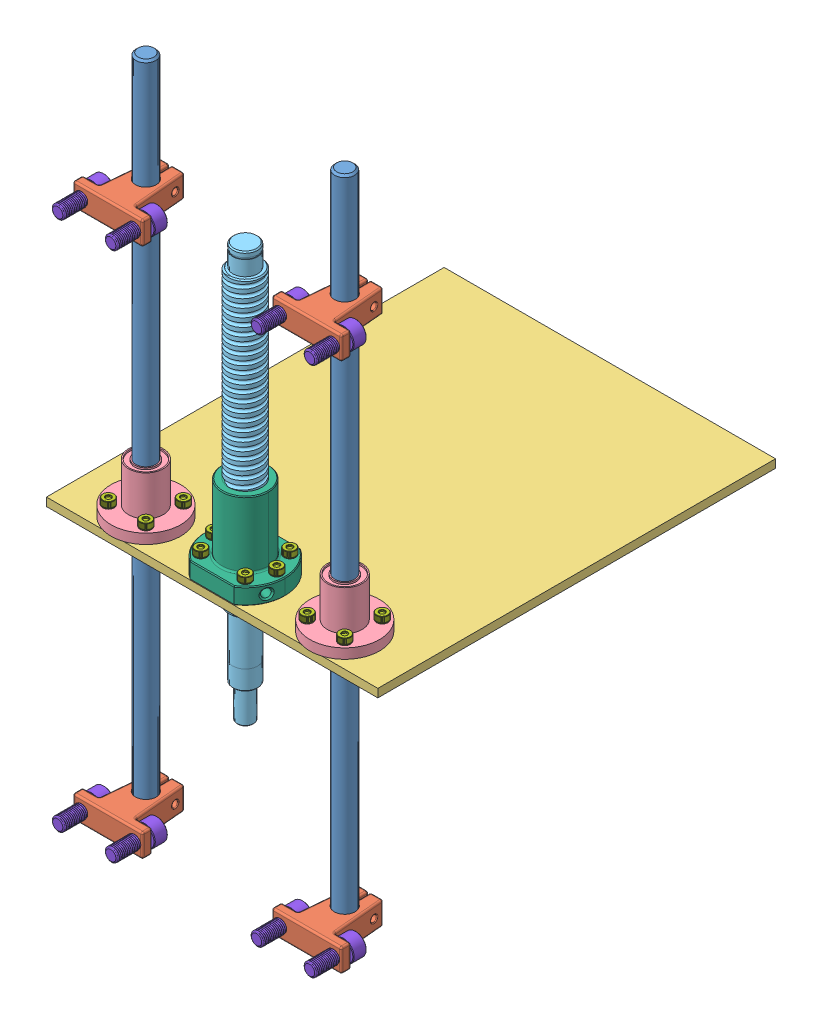
SolidWorks assembly Z_Axis_motion, configuration Default. Lengths in mm.
Overall size (200 400 257.52).
33 component instances, 8 part files, 23 mates.
Components (placement in the parent):
- 6112K104_Linear Motion Shaft-1: 6112K104_Linear Motion Shaft [6112K104] at (60 193 127) x (0.99915 0 0.041223) z (0 -1 0) size (12 12 400)
- 61815K34_Base-Mounted Shaft Support-1: 61815K34_Base-Mounted Shaft Support [61815K34] at (60 0 150) x (1 0 0) z (0 1 0) size (42 38 14)
- BuildPlate-1: BuildPlate [Default] at (0 145.6732 27) x (-1 0 0) z (0 0 -1) size (200 5 240)
- Linear Bearing-1: Linear Bearing [Default] at (-60 150.6732 127) x (-0.707107 0 0.707107) z (-0.707107 0 -0.707107) size (42 30 42)
- 61815K34_Base-Mounted Shaft Support-2: 61815K34_Base-Mounted Shaft Support [61815K34] at (60 320 150) x (1 0 0) z (0 1 0) size (42 38 14)
- 61815K34_Base-Mounted Shaft Support-3: 61815K34_Base-Mounted Shaft Support [61815K34] at (-60 0 150) x (1 0 0) z (0 1 0) size (42 38 14)
- 61815K34_Base-Mounted Shaft Support-4: 61815K34_Base-Mounted Shaft Support [61815K34] at (-60 320 150) x (1 0 0) z (0 1 0) size (42 38 14)
- Linear Bearing-2: Linear Bearing [Default] at (60 150.6732 127) x (-0.707107 0 -0.707107) z (0.707107 0 -0.707107) size (42 30 42)
- Generic Ballscrew-1: Generic Ballscrew [SFU-2005] at (0 74.038 127) x (-0.837169 0 -0.546944) z (0 -1 0) size (20 20.92 250)
- 6112K104_Linear Motion Shaft-2: 6112K104_Linear Motion Shaft [6112K104] at (-60 193 127) x (1 0 0) z (0 -1 0) size (12 12 400)
- SFU-1605.step-1: SFU-1605.step [Default] at (0 150.6732 127) x (1 0 0) z (0 -1 0) size (48 40 52.06)
- 91290A144_Black-Oxide Alloy Steel Socket Head Screw-1: 91290A144_Black-Oxide Alloy Steel Socket Head Screw [91290A144] at (71.3137 153.6732 138.3137) x (1 0 0) z (0 1 0) size (7 7 14.17)
- 91290A144_Black-Oxide Alloy Steel Socket Head Screw-2: 91290A144_Black-Oxide Alloy Steel Socket Head Screw [91290A144] at (48.6863 153.6732 138.3137) x (0 0 1) z (0 1 0) size (7 7 14.17)
- 91290A144_Black-Oxide Alloy Steel Socket Head Screw-3: 91290A144_Black-Oxide Alloy Steel Socket Head Screw [91290A144] at (48.6863 153.6732 115.6863) x (-1 0 0) z (0 1 0) size (7 7 14.17)
- 91290A144_Black-Oxide Alloy Steel Socket Head Screw-4: 91290A144_Black-Oxide Alloy Steel Socket Head Screw [91290A144] at (71.3137 153.6732 115.6863) x (0 0 -1) z (0 1 0) size (7 7 14.17)
- 91290A144_Black-Oxide Alloy Steel Socket Head Screw-5: 91290A144_Black-Oxide Alloy Steel Socket Head Screw [91290A144] at (-71.3137 153.6732 138.3137) x (1 0 0) z (0 1 0) size (7 7 14.17)
- 91290A144_Black-Oxide Alloy Steel Socket Head Screw-6: 91290A144_Black-Oxide Alloy Steel Socket Head Screw [91290A144] at (-48.6863 153.6732 138.3137) x (0 0 -1) z (0 1 0) size (7 7 14.17)
- 91290A144_Black-Oxide Alloy Steel Socket Head Screw-7: 91290A144_Black-Oxide Alloy Steel Socket Head Screw [91290A144] at (-48.6863 153.6732 115.6863) x (-1 0 0) z (0 1 0) size (7 7 14.17)
- 91290A144_Black-Oxide Alloy Steel Socket Head Screw-8: 91290A144_Black-Oxide Alloy Steel Socket Head Screw [91290A144] at (-71.3137 153.6732 115.6863) x (0 0 1) z (0 1 0) size (7 7 14.17)
- 96144A211_Fine-Thread Alloy Steel Socket Head Screw-1: 96144A211_Fine-Thread Alloy Steel Socket Head Screw [96144A211] at (76 0 164.1985) size (13 13 28.66)
- 96144A211_Fine-Thread Alloy Steel Socket Head Screw-2: 96144A211_Fine-Thread Alloy Steel Socket Head Screw [96144A211] at (44 0 164.1985) size (13 13 28.66)
- 96144A211_Fine-Thread Alloy Steel Socket Head Screw-3: 96144A211_Fine-Thread Alloy Steel Socket Head Screw [96144A211] at (44 320 164.1985) size (13 13 28.66)
- 96144A211_Fine-Thread Alloy Steel Socket Head Screw-4: 96144A211_Fine-Thread Alloy Steel Socket Head Screw [96144A211] at (-76 0 164.1985) size (13 13 28.66)
- 96144A211_Fine-Thread Alloy Steel Socket Head Screw-5: 96144A211_Fine-Thread Alloy Steel Socket Head Screw [96144A211] at (-76 320 164.1985) size (13 13 28.66)
- 96144A211_Fine-Thread Alloy Steel Socket Head Screw-6: 96144A211_Fine-Thread Alloy Steel Socket Head Screw [96144A211] at (76 320 164.1985) size (13 13 28.66)
- 96144A211_Fine-Thread Alloy Steel Socket Head Screw-7: 96144A211_Fine-Thread Alloy Steel Socket Head Screw [96144A211] at (-44 0 164.1985) size (13 13 28.66)
- 96144A211_Fine-Thread Alloy Steel Socket Head Screw-8: 96144A211_Fine-Thread Alloy Steel Socket Head Screw [96144A211] at (-44 320 164.1985) size (13 13 28.66)
- 91290A144_Black-Oxide Alloy Steel Socket Head Screw-9: 91290A144_Black-Oxide Alloy Steel Socket Head Screw [91290A144] at (-13.435 157.6732 113.565) x (1 0 0) z (0 1 0) size (7 7 14.17)
- 91290A144_Black-Oxide Alloy Steel Socket Head Screw-10: 91290A144_Black-Oxide Alloy Steel Socket Head Screw [91290A144] at (-19 157.6732 127) x (0.707107 0 -0.707107) z (0 1 0) size (7 7 14.17)
- 91290A144_Black-Oxide Alloy Steel Socket Head Screw-11: 91290A144_Black-Oxide Alloy Steel Socket Head Screw [91290A144] at (-13.435 157.6732 140.435) x (0 0 -1) z (0 1 0) size (7 7 14.17)
- 91290A144_Black-Oxide Alloy Steel Socket Head Screw-12: 91290A144_Black-Oxide Alloy Steel Socket Head Screw [91290A144] at (13.435 157.6732 113.565) x (1 0 0) z (0 1 0) size (7 7 14.17)
- 91290A144_Black-Oxide Alloy Steel Socket Head Screw-13: 91290A144_Black-Oxide Alloy Steel Socket Head Screw [91290A144] at (19 157.6732 127) x (0.707107 0 0.707107) z (0 1 0) size (7 7 14.17)
- 91290A144_Black-Oxide Alloy Steel Socket Head Screw-14: 91290A144_Black-Oxide Alloy Steel Socket Head Screw [91290A144] at (13.435 157.6732 140.435) x (0 0 1) z (0 1 0) size (7 7 14.17)
Mates (geometry in assembly coordinates):
- Concentric1: concentric anti-aligned: cylinder of 6112K104_Linear Motion Shaft-1 through (60 -7 127) axis (0 1 0) radius 6; cylinder of 61815K34_Base-Mounted Shaft Support-1 through (60 7 127) axis (0 -1 0) radius 6
- Coincident36: coincident aligned: plane of 6112K104_Linear Motion Shaft-1 through (60 -7 127) normal (0 -1 0); plane of 61815K34_Base-Mounted Shaft Support-1 through (60 -7 150) normal (0 -1 0)
- Concentric3: concentric anti-aligned: cylinder of BuildPlate-1 through (-60 145.6732 127) axis (0 1 0) radius 10.75; cylinder of Linear Bearing-1 through (-60 156.6732 127) axis (0 -1 0) radius 6
- Coincident37: coincident anti-aligned: plane of BuildPlate-1 through (0 150.6732 27) normal (0 1 0); plane of Linear Bearing-1 through (-60 150.6732 127) normal (0 -1 0)
- Concentric4: concentric aligned: cylinder of BuildPlate-1 through (-48.6863 145.6732 115.6863) axis (0 1 0) radius 3.4; cylinder of Linear Bearing-1 through (-48.6863 150.6732 115.6863) axis (0 1 0) radius 3.4
- Concentric19: concentric anti-aligned: cylinder of 6112K104_Linear Motion Shaft-1 through (60 -7 127) axis (0 1 0) radius 6; cylinder of Linear Bearing-2 through (60 156.6732 127) axis (0 -1 0) radius 6
- Concentric20: concentric anti-aligned: cylinder of BuildPlate-1 through (60 145.6732 127) axis (0 1 0) radius 10.75; cylinder of Linear Bearing-2 through (60 156.6732 127) axis (0 -1 0) radius 6
- Coincident69: coincident anti-aligned: plane of BuildPlate-1 through (0 150.6732 27) normal (0 1 0); plane of Linear Bearing-2 through (60 150.6732 127) normal (0 -1 0)
- Concentric21: concentric aligned: cylinder of BuildPlate-1 through (71.3137 145.6732 138.3137) axis (0 1 0) radius 3.4; cylinder of Linear Bearing-2 through (71.3137 150.6732 138.3137) axis (0 1 0) radius 3.4
- Concentric25: concentric anti-aligned: cylinder of Linear Bearing-1 through (-60 156.6732 127) axis (0 -1 0) radius 6; cylinder of 6112K104_Linear Motion Shaft-2 through (-60 -7 127) axis (0 1 0) radius 6
- Concentric26: concentric anti-aligned: cylinder of 61815K34_Base-Mounted Shaft Support-3 through (-60 7 127) axis (0 -1 0) radius 6; cylinder of 6112K104_Linear Motion Shaft-2 through (-60 -7 127) axis (0 1 0) radius 6
- Coincident71: coincident aligned: plane of 6112K104_Linear Motion Shaft-2 through (-60 -7 127) normal (0 -1 0); plane of 61815K34_Base-Mounted Shaft Support-3 through (-60 -7 150) normal (0 -1 0)
- Concentric23: concentric anti-aligned: cylinder of BuildPlate-1 through (0 145.6732 127) axis (0 1 0) radius 8.25; cylinder of SFU-1605.step-1 through (0 125.654 127) axis (0 -1 0) radius 14
- Coincident70: coincident anti-aligned: plane of BuildPlate-1 through (0 150.6732 27) normal (0 1 0); plane of SFU-1605.step-1 through (0 150.6732 151) normal (0 -1 0)
- Concentric24: concentric anti-aligned: cylinder of BuildPlate-1 through (-19 145.6732 127) axis (0 1 0) radius 2.75; cylinder of SFU-1605.step-1 through (-19 200.6732 127) axis (0 -1 0) radius 2.75
- Concentric27: concentric anti-aligned: cylinder of Linear Bearing-2 through (71.3137 150.6732 138.3137) axis (0 1 0) radius 3.4; circle of 91290A144_Black-Oxide Alloy Steel Socket Head Screw-1
- Coincident72: coincident anti-aligned: plane of Linear Bearing-2 through (60 156.6732 127) normal (0 1 0); plane of 91290A144_Black-Oxide Alloy Steel Socket Head Screw-1 through (68.0137 156.6732 138.3137) normal (0 -1 0)
- Concentric28: concentric anti-aligned: circle of 61815K34_Base-Mounted Shaft Support-1; circle of 96144A211_Fine-Thread Alloy Steel Socket Head Screw-1
- Coincident73: coincident anti-aligned: plane of 61815K34_Base-Mounted Shaft Support-1 through (71 7 144.1985) normal (0 0 -1); plane of 96144A211_Fine-Thread Alloy Steel Socket Head Screw-1 through (76 0 144.1985) normal (0 0 1)
- Coincident74: coincident anti-aligned: plane of 61815K34_Base-Mounted Shaft Support-1 through (49 7 144.1985) normal (0 0 -1); plane of 96144A211_Fine-Thread Alloy Steel Socket Head Screw-2 through (44 0 144.1985) normal (0 0 1)
- Concentric29: concentric aligned: cylinder of 61815K34_Base-Mounted Shaft Support-1 through (44 0 112) axis (0 0 1) radius 3; cylinder of 96144A211_Fine-Thread Alloy Steel Socket Head Screw-2 through (44 0 136.1985) axis (0 0 1) radius 6.5
- Coincident75: coincident anti-aligned: plane of SFU-1605.step-1 through (0 160.6732 141) normal (0 1 0); plane of 91290A144_Black-Oxide Alloy Steel Socket Head Screw-9 through (-16.735 160.6732 113.565) normal (0 -1 0)
- Concentric31: concentric aligned: cylinder of SFU-1605.step-1 through (-13.435 200.6732 113.565) axis (0 -1 0) radius 2.75; circle of 91290A144_Black-Oxide Alloy Steel Socket Head Screw-9
